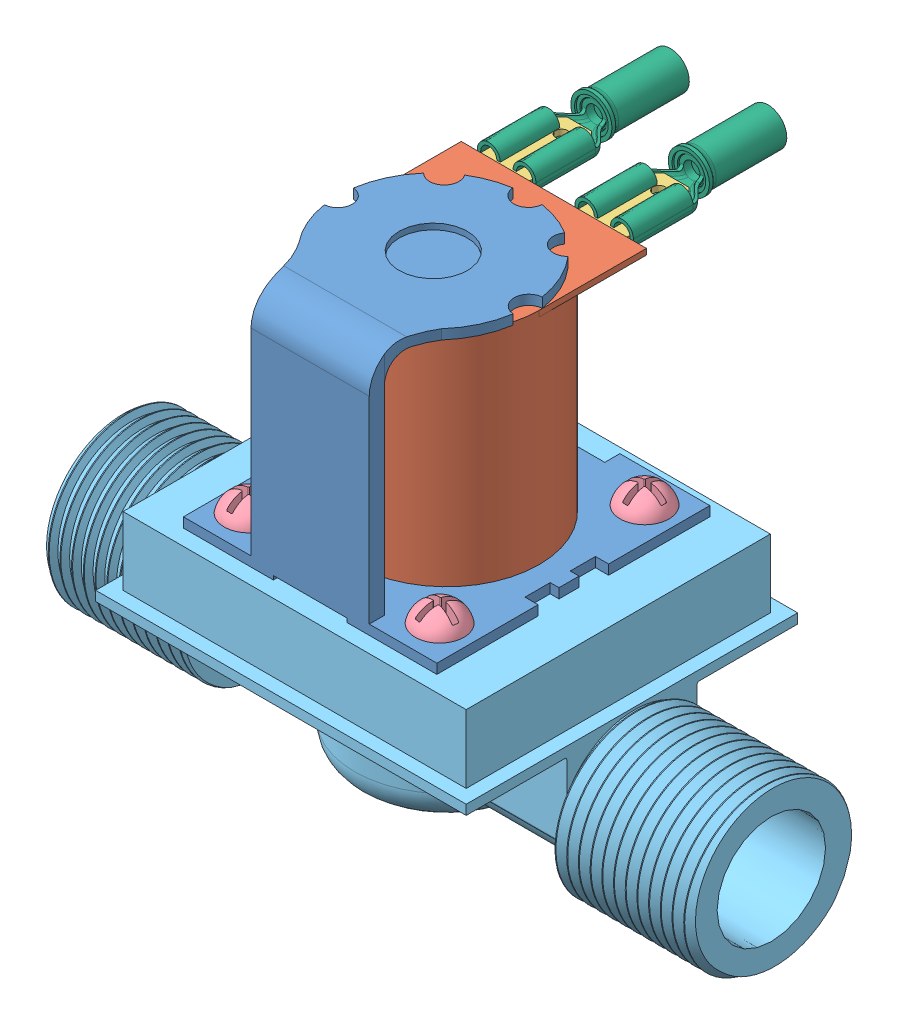
SolidWorks assembly assemb2, configuration Default. Lengths in mm.
Overall size (86.62 62.65 56.94).
11 component instances, 6 part files, 23 mates.
Components (placement in the parent):
- CAGE-1: CAGE [Default] at (19.7626 3.5184 23.3683) size (33.02 31.56 35.56)
- cylinder-1: cylinder [Default] at (19.7626 4.7884 23.3683) size (24.13 28.7 26.04)
- LEAD-1: LEAD [Default] at (26.1126 32.7284 4.5723) x (-1 0 0) z (0 0 -1) size (6.35 0.76 9.65)
- LEAD-2: LEAD [Default] at (13.4126 32.7284 4.5723) x (-1 0 0) z (0 0 -1) size (6.35 0.76 9.65)
- screw-1: screw [Default] at (32.2026 5.045 36.7183) x (-0.98735 0 -0.158557) z (0.158557 0 -0.98735) size (6.35 10.12 6.35)
- screw-2: screw [Default] at (32.2026 5.045 10.0183) size (6.35 10.12 6.35)
- screw-3: screw [Default] at (7.3226 5.045 10.0183) x (0.998132 0 0.061096) z (-0.061096 0 0.998132) size (6.35 10.12 6.35)
- screw-4: screw [Default] at (7.3226 5.045 36.7183) size (6.35 10.12 6.35)
- Solenoid-1: Solenoid [Default] at (-22.4864 -15.5316 23.4003) x (1 0 0) z (0 -1 0) size (86.62 43.18 29.68)
- 55675-1-1: 55675-1 [Default] at (26.3132 32.2814 9.3983) size (7.65 5.36 21.35)
- 55675-1-2: 55675-1 [Default] at (13.6132 32.2814 9.3983) size (7.65 5.36 21.35)
Mates (geometry in assembly coordinates):
- Coincident1: coincident aligned: circle of CAGE-1; circle of screw-1
- ProfileCenter2: profile center anti-aligned: plane of cylinder-1 through (19.7626 4.7884 23.3683) normal (0 -1 0)
- Coincident4: coincident anti-aligned: circle of CAGE-1; circle of screw-2
- Coincident5: coincident aligned: circle of CAGE-1; circle of screw-3
- Coincident6: coincident anti-aligned: circle of CAGE-1; circle of screw-4
- Coincident9: coincident anti-aligned: plane of cylinder-1 through (31.8276 32.7284 9.3983) normal (0 0 -1); plane of LEAD-1 through (22.9376 32.7284 9.3983) normal (0 0 1)
- Coincident10: coincident aligned: plane of cylinder-1 through (19.7626 33.4904 16.3833) normal (0 1 0); plane of LEAD-1 through (26.1126 33.4904 4.9047) normal (0 1 0)
- Parallel3: parallel aligned: plane of CAGE-1 through (24.5531 3.5184 7.5568) normal (0 0 -1); plane of cylinder-1 through (31.8276 32.7284 9.3983) normal (0 0 -1)
- Coincident13: coincident anti-aligned: plane of cylinder-1 through (31.8276 32.7284 9.3983) normal (0 0 -1); plane of LEAD-2 through (10.2376 32.7284 9.3983) normal (0 0 1)
- Coincident15: coincident aligned: plane of cylinder-1 through (19.7626 33.4904 16.3833) normal (0 1 0); plane of LEAD-2 through (13.4126 33.4904 4.9047) normal (0 1 0)
- Distance2: distance = 2.54 mm aligned: plane of cylinder-1 through (31.8276 32.7284 23.3683) normal (1 0 0); plane of LEAD-1 through (29.2876 32.7284 9.3983) normal (1 0 0)
- Distance3: distance = 2.54 mm aligned: plane of LEAD-2 through (10.2376 32.7284 1.3338) normal (-1 0 0); plane of cylinder-1 through (7.6976 32.7284 9.3983) normal (-1 0 0)
- Parallel19: parallel aligned: plane of CAGE-1 through (3.2526 3.5184 41.1483) normal (0 0 1); plane of Solenoid-1 through (42.1566 -0.2916 43.2123) normal (0 0 1)
- Distance5: distance = 5.8 mm aligned: plane of CAGE-1 through (3.2526 3.5184 5.5883) normal (-1 0 0); plane of Solenoid-1 through (-2.5474 -0.2916 43.2123) normal (-1 0 0)
- Distance6: distance = 2 mm aligned: plane of CAGE-1 through (36.2726 3.5184 5.5883) normal (0 0 -1); plane of Solenoid-1 through (-2.5474 -0.2916 3.5883) normal (0 0 -1)
- Coincident26: coincident anti-aligned: plane of LEAD-1 through (26.1126 32.7284 4.9047) normal (0 -1 0); plane of 55675-1-1 through (29.2419 32.7284 9.3983) normal (0 1 0)
- Coincident27: coincident anti-aligned: plane of LEAD-1 through (22.9376 32.7284 1.3338) normal (-1 0 0); plane of 55675-1-1 through (22.9376 33.1755 9.3983) normal (1 0 0)
- Parallel15: parallel anti-aligned: plane of LEAD-1 through (29.2876 32.7284 9.3983) normal (1 0 0); plane of 55675-1-1 through (29.6889 33.6936 9.3983) normal (-1 0 0)
- Coincident30: coincident anti-aligned: plane of cylinder-1 through (31.8276 32.7284 9.3983) normal (0 0 -1); plane of 55675-1-1 through (26.3132 32.2814 9.3983) normal (0 0 1)
- Coincident32: coincident anti-aligned: plane of LEAD-2 through (13.4126 32.7284 4.9047) normal (0 -1 0); plane of 55675-1-2 through (16.5419 32.7284 9.3983) normal (0 1 0)
- Coincident33: coincident anti-aligned: plane of LEAD-2 through (10.2376 32.7284 1.3338) normal (-1 0 0); plane of 55675-1-2 through (10.2376 33.1755 9.3983) normal (1 0 0)
- Parallel17: parallel anti-aligned: plane of LEAD-2 through (16.5876 32.7284 9.3983) normal (1 0 0); plane of 55675-1-2 through (16.9889 33.6936 9.3983) normal (-1 0 0)
- Coincident35: coincident anti-aligned: plane of cylinder-1 through (31.8276 32.7284 9.3983) normal (0 0 -1); plane of 55675-1-2 through (13.6132 32.2814 9.3983) normal (0 0 1)
